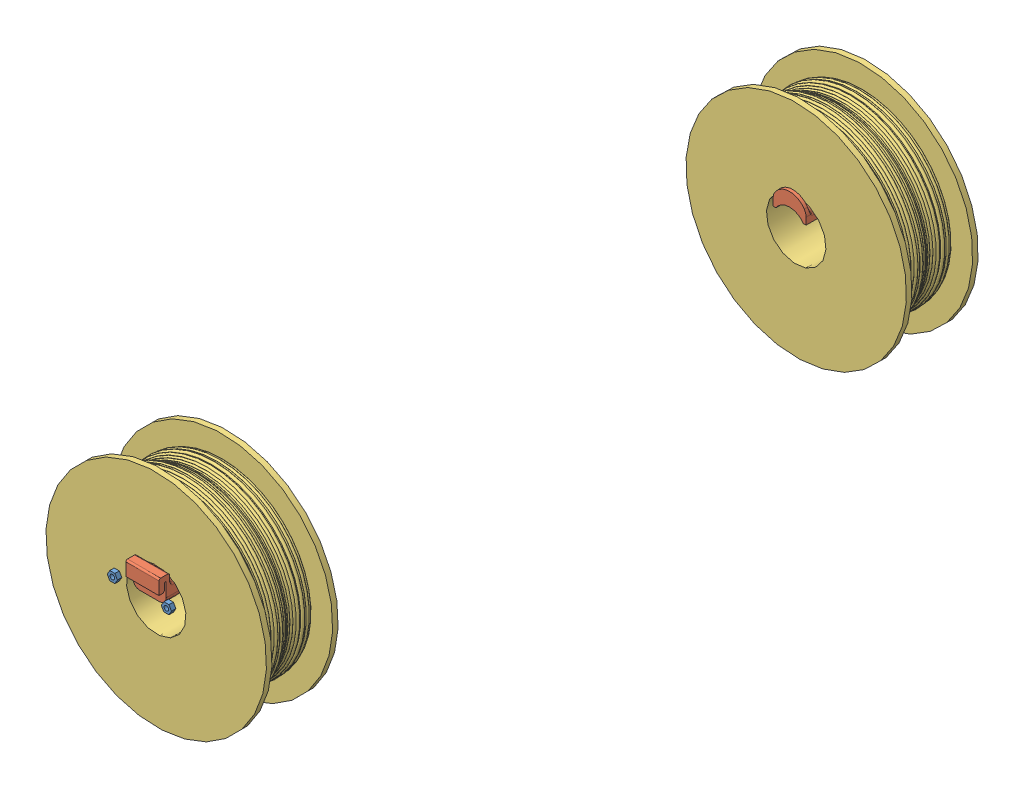
SolidWorks assembly 040M08C01.0P00Spool mount, configuration Fasteners. Lengths in mm.
Overall size (281.26 281.26 675.5).
10 component instances, 4 part files, 25 mates.
Components (placement in the parent):
- DIN934 M5-1: DIN934 M5 [Predeterminado] at (-28.16 39.3967 27.4257) x (1 0 0) z (0 1 0) size (9.24 4 8)
- DIN934 M5-2: DIN934 M5 [Predeterminado] at (20.84 39.3967 27.4257) x (1 0 0) z (0 1 0) size (9.24 4 8)
- DIN934 M5-3: DIN934 M5 [Predeterminado] at (20.84 39.3967 698.9257) x (1 0 0) z (0 1 0) size (9.24 4 8)
- DIN934 M5-4: DIN934 M5 [Predeterminado] at (-28.16 39.3967 698.9257) x (1 0 0) z (0 1 0) size (9.24 4 8)
- BCN3DSigma-M08C01.0P01C Spool holder-1: BCN3DSigma-M08C01.0P01C Spool holder [Predeterminado] at (11.34 43.2058 26.1757) x (0 0 1) z (-1 0 0) size (83.5 27.54 31.19)
- BCN3DSigma-M08C01.0P01C Spool holder-2: BCN3DSigma-M08C01.0P01C Spool holder [Predeterminado] at (-18.66 43.2058 696.1757) x (0 0 -1) z (1 0 0) size (83.5 27.54 31.19)
- BCN3DSigma-M08C01.0P02A Spool support-2: BCN3DSigma-M08C01.0P02A Spool support [Predeterminado] at (-3.66 28.8967 699.9257) x (-1 0 0) z (0 0 -1) (suppressed, hidden)
- BCN3DSigma-M08C01.0P02A Spool support-1: BCN3DSigma-M08C01.0P02A Spool support [Predeterminado] at (-3.66 28.8967 22.4257) (suppressed, hidden)
- BCN3DSigma-M08C01.0P03Z Small spool-2: BCN3DSigma-M08C01.0P03Z Small spool [Predeterminado] at (-66.5061 -51.3264 651.1757) x (0 0 1) z (-0.777841 0.628461 0) size (65 200 200)
- BCN3DSigma-M08C01.0P03Z Small spool-1: BCN3DSigma-M08C01.0P03Z Small spool [Predeterminado] at (-10.754 -73.2904 71.1757) x (0 0 1) z (-0.997481 0.07094 0) size (65 200 200)
Mates (geometry in assembly coordinates):
- Ancho1: width: plane of BCN3DSigma-M08C01.0P01C Spool holder-1 through (-18.66 56.2058 35.6757) normal (0 0 1); plane of BCN3DSigma-M08C01.0P01C Spool holder-1 through (11.34 43.2058 106.6757) normal (0 0 -1); plane of BCN3DSigma-M08C01.0P03Z Small spool-1 through (-5.5753 -0.4743 38.6757) normal (0 0 -1); plane of BCN3DSigma-M08C01.0P03Z Small spool-1 through (-10.754 -73.2904 103.6757) normal (0 0 1)
- Ancho2: width: plane of BCN3DSigma-M08C01.0P02A Spool support-1 through (-19.66 49.8967 31.4257) normal (0 0 -1); plane of BCN3DSigma-M08C01.0P02A Spool support-1 through (-19.66 49.8967 32.4257) normal (0 0 1); plane of BCN3DSigma-M08C01.0P01C Spool holder-1 through (-18.66 32.2058 32.6757) normal (0 0 -1); plane of BCN3DSigma-M08C01.0P01C Spool holder-1 through (-18.66 51.2058 31.1757) normal (0 0 1)
- Ancho3: width: plane of BCN3DSigma-M08C01.0P01C Spool holder-1 through (-18.66 43.2058 26.1757) normal (-1 0 0); plane of BCN3DSigma-M08C01.0P01C Spool holder-1 through (11.34 43.2058 26.1757) normal (1 0 0); plane of BCN3DSigma-M08C01.0P02A Spool support-1 through (-19.66 49.8967 22.4257) normal (1 0 0); plane of BCN3DSigma-M08C01.0P02A Spool support-1 through (12.34 49.8967 31.4257) normal (-1 0 0)
- Bloquear1: lock: unknown of BCN3DSigma-M08C01.0P02A Spool support-1
- Ancho4: width: plane of BCN3DSigma-M08C01.0P01C Spool holder-1 through (-18.66 43.2058 26.1757) normal (-1 0 0); plane of BCN3DSigma-M08C01.0P01C Spool holder-1 through (11.34 43.2058 26.1757) normal (1 0 0); cylinder of BCN3DSigma-M08C01.0P03Z Small spool-1 through (-3.66 26.4577 16.2966) axis (0 0 -1) radius 27
- Coincidente2: coincident: plane of BCN3DSigma-M08C01.0P02A Spool support-1 through (-34.66 49.8967 23.4257) normal (0 0 1); plane of DIN934 M5-1 through (-30.4694 35.3967 23.4257) normal (0 0 -1)
- Concéntrica2: concentric: cylinder of BCN3DSigma-M08C01.0P02A Spool support-1 through (-28.16 39.3967 22.4257) axis (0 0 1) radius 2.6; cylinder of DIN934 M5-1 through (-28.16 39.3967 23.4257) axis (0 0 1) radius 2.1
- Coincidente3: coincident: plane of BCN3DSigma-M08C01.0P02A Spool support-1 through (12.34 49.8967 23.4257) normal (0 0 1); plane of DIN934 M5-2 through (18.5306 35.3967 23.4257) normal (0 0 -1)
- Concéntrica3: concentric: cylinder of BCN3DSigma-M08C01.0P02A Spool support-1 through (20.84 39.3967 22.4257) axis (0 0 1) radius 2.6; cylinder of DIN934 M5-2 through (20.84 39.3967 23.4257) axis (0 0 1) radius 2.1
- Coincidente4: coincident: plane of DIN934 M5-1 through (-30.4694 43.3967 23.4257) normal (0 1 0); plane of DIN934 M5-2 through (18.5306 43.3967 23.4257) normal (0 1 0)
- Tangente4: tangent: cylinder of BCN3DSigma-M08C01.0P03Z Small spool-1 through (-3.66 26.4577 16.2966) axis (0 0 -1) radius 27; cylinder of BCN3DSigma-M08C01.0P01C Spool holder-1 through (-8.66 42.7058 106.6757) axis (0 0 -1) radius 10
- Width1: width: plane of BCN3DSigma-M08C01.0P01C Spool holder-2 through (-18.66 43.2058 615.6757) normal (0 0 1); plane of BCN3DSigma-M08C01.0P01C Spool holder-2 through (11.34 56.2058 686.6757) normal (0 0 -1); plane of BCN3DSigma-M08C01.0P03Z Small spool-2 through (-20.6284 5.456 618.6757) normal (0 0 -1); plane of BCN3DSigma-M08C01.0P03Z Small spool-2 through (-66.5061 -51.3264 683.6757) normal (0 0 1)
- Width3: width: plane of BCN3DSigma-M08C01.0P02A Spool support-2 through (12.34 49.8967 690.9257) normal (0 0 1); plane of BCN3DSigma-M08C01.0P02A Spool support-2 through (12.34 49.8967 689.9257) normal (0 0 -1); plane of BCN3DSigma-M08C01.0P01C Spool holder-2 through (11.34 32.2058 689.6757) normal (0 0 1); plane of BCN3DSigma-M08C01.0P01C Spool holder-2 through (11.34 51.2058 691.1757) normal (0 0 -1)
- Width4: width: plane of BCN3DSigma-M08C01.0P02A Spool support-2 through (12.34 49.8967 699.9257) normal (-1 0 0); plane of BCN3DSigma-M08C01.0P02A Spool support-2 through (-19.66 49.8967 690.9257) normal (1 0 0); plane of BCN3DSigma-M08C01.0P01C Spool holder-2 through (11.34 43.2058 696.1757) normal (1 0 0); plane of BCN3DSigma-M08C01.0P01C Spool holder-2 through (-18.66 43.2058 696.1757) normal (-1 0 0)
- Width5: width: plane of BCN3DSigma-M08C01.0P01C Spool holder-2 through (-18.66 43.2058 696.1757) normal (-1 0 0); plane of BCN3DSigma-M08C01.0P01C Spool holder-2 through (11.34 43.2058 696.1757) normal (1 0 0); cylinder of BCN3DSigma-M08C01.0P03Z Small spool-2 through (-3.66 26.4577 596.2966) axis (0 0 -1) radius 27
- Tangent1: tangent: cylinder of BCN3DSigma-M08C01.0P03Z Small spool-2 through (-3.66 26.4577 596.2966) axis (0 0 -1) radius 27; cylinder of BCN3DSigma-M08C01.0P01C Spool holder-2 through (-8.66 42.7058 615.6757) axis (0 0 1) radius 10
- Coincident5: coincident: plane of BCN3DSigma-M08C01.0P01C Spool holder-1 through (-18.66 56.2058 26.1757) normal (0 1 0); plane of BCN3DSigma-M08C01.0P01C Spool holder-2 through (11.34 56.2058 696.1757) normal (0 1 0)
- Coincident6: coincident: plane of BCN3DSigma-M08C01.0P01C Spool holder-1 through (-18.66 43.2058 26.1757) normal (-1 0 0); plane of BCN3DSigma-M08C01.0P01C Spool holder-2 through (-18.66 43.2058 696.1757) normal (-1 0 0)
- Distance1: distance = 515 mm: plane of BCN3DSigma-M08C01.0P03Z Small spool-1 through (-10.754 -73.2904 103.6757) normal (0 0 1); plane of BCN3DSigma-M08C01.0P03Z Small spool-2 through (-20.6284 5.456 618.6757) normal (0 0 -1)
- Concéntrica4: concentric: cylinder of BCN3DSigma-M08C01.0P02A Spool support-2 through (20.84 39.3967 699.9257) axis (0 0 -1) radius 2.6; cylinder of DIN934 M5-3 through (20.84 39.3967 694.9257) axis (0 0 1) radius 2.1
- Coincidente5: coincident: plane of BCN3DSigma-M08C01.0P02A Spool support-2 through (27.34 49.8967 698.9257) normal (0 0 -1); plane of DIN934 M5-3 through (18.5306 35.3967 698.9257) normal (0 0 1)
- Concéntrica5: concentric: cylinder of BCN3DSigma-M08C01.0P02A Spool support-2 through (-28.16 39.3967 699.9257) axis (0 0 -1) radius 2.6; cylinder of DIN934 M5-4 through (-28.16 39.3967 694.9257) axis (0 0 1) radius 2.1
- Coincidente6: coincident: plane of BCN3DSigma-M08C01.0P02A Spool support-2 through (-19.66 49.8967 698.9257) normal (0 0 -1); plane of DIN934 M5-4 through (-30.4694 35.3967 698.9257) normal (0 0 1)
- Coincidente7: coincident: cylinder of BCN3DSigma-M08C01.0P01C Spool holder-2 through (11.34 50.4558 690.4257) axis (1 0 0) radius 0.75; line of BCN3DSigma-M08C01.0P02A Spool support-2 through (11.34 49.8967 689.9257) axis (-1 0 0)
- Coincidente8: coincident: line of BCN3DSigma-M08C01.0P02A Spool support-1 through (-18.66 49.8967 32.4257) axis (1 0 0); cylinder of BCN3DSigma-M08C01.0P01C Spool holder-1 through (-18.66 50.4558 31.9257) axis (-1 0 0) radius 0.75
